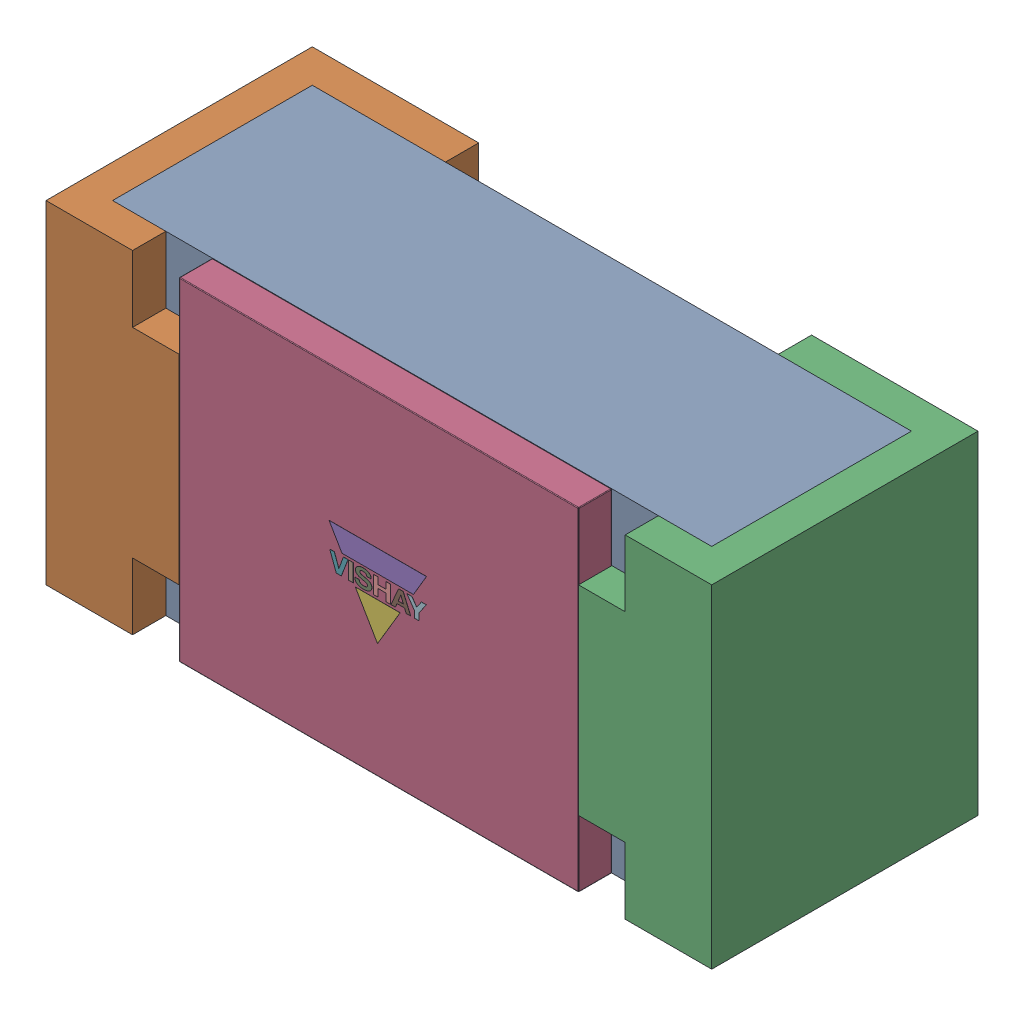
SolidWorks assembly Res_Vishay_CRCW04021K00FKED_eec.step, configuration Default. Lengths in mm.
Overall size (1 0.5 0.4).
5 component instances, 4 part files, 0 mates.
Components (placement in the parent):
- body.step-1: body.step [Default] at (0 0 0.35) x (1 0 0) z (0 0 -1) size (0.9 0.5 0.3)
- pad.step-1: pad.step [Default] at (-0.3133 -0.25 0.4) x (1 0 0) z (0 1 0) size (0.25 0.4 0.5)
- pad.step-2: pad.step [Default] at (0.3133 0.25 0.4) x (-1 0 0) z (0 -1 0) size (0.25 0.4 0.5)
- top.step-1: top.step [Default] at (0 0 0.4) x (1 0 0) z (0 0 -1) size (0.6 0.5 0.05)
- Vishay.step-1: Vishay.step [Default] at (0.0437 -0.9162 0.4) size (0.15 0.12 0)
